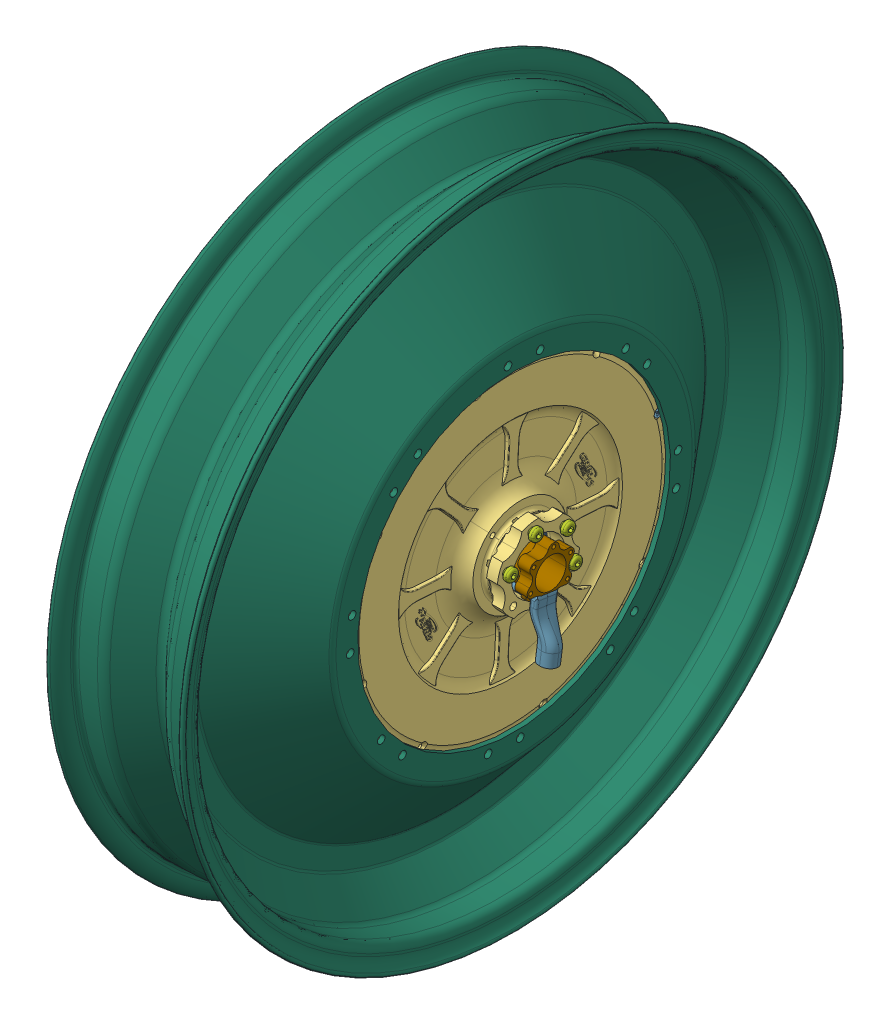
SolidWorks assembly ALL-AXLE_V2, configuration Default. Lengths in mm.
Overall size (124.24 447.81 475.17).
21 component instances, 15 part files, 2 mates.
Components (placement in the parent):
- ALL-AXLE_V2.IGS-1: ALL-AXLE_V2.IGS [Default] at origin size (114.75 446.96 475.17)
  - 6 Spoke Stator Core.IGS-1: 6 Spoke Stator Core.IGS [Default] at (-52 0 0) x (-1 0 0) z (0 -0.866025 0.5) size (31.89 164.63 166.19)
  - Lamination Stack.IGS-1: Lamination Stack.IGS [Default] at (-53.5 0 0) x (0 0.744777 0.667313) z (1 0 0) size (198.09 198 27.96)
  - Left Plate with Logo.IGS-1: Left Plate with Logo.IGS [Default] at (-31 0 0) x (1 0 0) z (0 0.7476 0.664149) size (28.12 418.01 226.51)
  - Right Plate with Logo.IGS-1: Right Plate with Logo.IGS [Default] at (-76 0 0) x (-1 0 0) z (0 -0.862804 -0.505539) size (14.77 418.01 226.51)
  - M2.5 Bolt.IGS-1: M2.5 Bolt.IGS [Default] at (-80.35 28.6185 -97.0692) x (0 -0.881636 0.47193) z (0 0.47193 0.881636) size (5.51 53.51 5.51)
  - M2.5 nut.IGS-1: M2.5 nut.IGS [Default] at (-78.5 28.6185 -97.0692) x (0 0.55009 0.835106) z (-1 0 0) size (5.01 5.78 2.01)
  - M5 Disk Bolt.IGS-1: M5 Disk Bolt.IGS [Default] at (-13.2 6.938 20.8773) x (0 -1 0) z (0 0 1) size (10.01 10.01 8.01)
  - M5 Disk Bolt.IGS-2: M5 Disk Bolt.IGS [Default] at (-13.2 21.5493 4.4301) x (0 -1 0) z (0 0 1) size (10.01 10.01 8.01)
  - M5 Disk Bolt.IGS-3: M5 Disk Bolt.IGS [Default] at (-13.2 -6.938 -20.8773) x (0 -1 0) z (0 0 1) size (10.01 10.01 8.01)
  - M5 Disk Bolt.IGS-4: M5 Disk Bolt.IGS [Default] at (-13.2 14.6113 -16.4472) x (0 -1 0) z (0 0 1) size (10.01 10.01 8.01)
  - Undulating Rotor.IGS-1: Undulating Rotor.IGS [Default] at (-53.5 0 0) size (47 211.4 211.4)
  - Axle 35mm Bearing, Full Slot.IGS-1: Axle 35mm Bearing, Full Slot.IGS [Default] x (1 0 0) z (0 0.145559 0.98935) size (95.23 67.01 60.01)
  - 35 x 55 bearing.IGS-1: 35 x 55 bearing.IGS [Default] at (-28.5 0 0) x (0 -0.007614 -0.999971) z (1 0 0) size (55 108.01 10.01)
  - 35 x 55 bearing.IGS-2: 35 x 55 bearing.IGS [Default] at (-78.5 0 0) x (0 0.235768 0.971809) z (-1 0 0) size (55 108.01 10.01)
  - 35mm Bearing Shim.IGS-1: 35mm Bearing Shim.IGS [Default] at (-83.5 0 0) x (0 0.002382 0.999997) z (-1 0 0) size (60.51 60.51 10.56)
  - 35mm Bearing Shim.IGS-2: 35mm Bearing Shim.IGS [Default] at (-23.5 0 0) x (0 0 -1) z (1 0 0) size (60.51 60.51 10.56)
  - ThruAxleTorqueArm_35mm.IGS-1: ThruAxleTorqueArm_35mm.IGS [Default] at (-86.25 0 0) x (0 0.145559 0.98935) z (-1 0 0) size (120.78 130.17 6.5)
  - Fork Mount r4.IGS-1: Fork Mount r4.IGS [Default] at (-97.85 86.4258 -89.252) x (-1 0 0) z (0 -0.814467 0.58021) size (12.51 21.76 35.01)
  - Cusmade Cable Overmold.IGS-1: Cusmade Cable Overmold.IGS [Default] at (-36.2 -10.6084 1.4056) x (0 0.145559 0.98935) z (1 0 0) size (14.44 34.78 46.85)
- spun wheel125-1: spun wheel125 [Default] at (-72.0065 0 0) x (0 -0.999309 -0.03718) z (0 0.03718 -0.999309) size (432.05 89.72 432.05)
Mates (geometry in assembly coordinates):
- Tangent2: tangent: plane of assembly; face of ALL-AXLE_V2.IGS-1/Left Plate with Logo.IGS-1; plane of spun wheel125-1 through (-27 116.0169 4.3165) normal (-1 0 0)
- Coincident1: coincident: line of spun wheel-1 through (-312.8955 0 0) axis (1 0 0)
